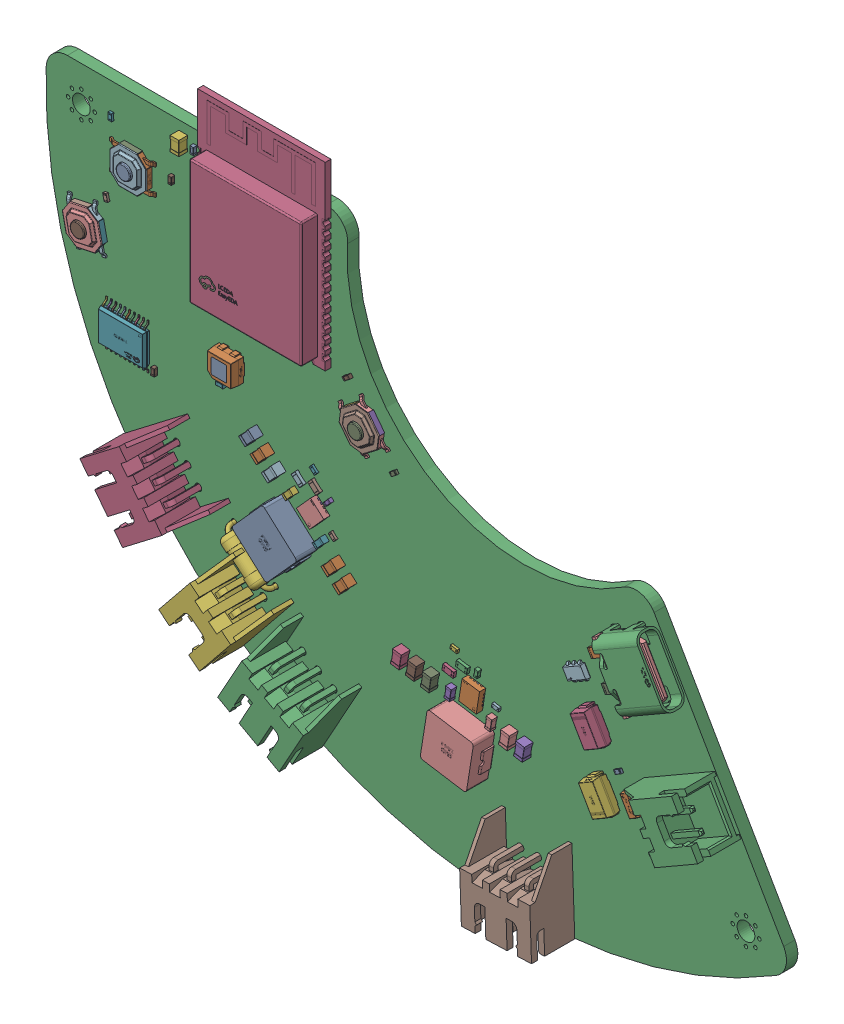
SolidWorks assembly head_control_board(2), configuration Default. Lengths in mm.
Overall size (104.47 78.47 9.5).
115 component instances, 20 part files, 0 mates.
Components (placement in the parent):
- C_0402_1005Metric-1: C_0402_1005Metric [Default] at (-31.1333 33.9184 1.65) x (0 -1 0) z (0 0 1) size (1 0.5 0.5)
  - C_0402_1005Metric-0-1: C_0402_1005Metric-0 [Default] at origin size (1 0.5 0.5)
- R_0805_2012Metric-1: R_0805_2012Metric [Default] at (25.7526 1.0179 1.65) x (0.866025 0.5 0) z (0 0 1) size (2 1.2 0.45)
  - R_0805_2012Metric-1-1: R_0805_2012Metric-1 [Default] at origin size (2 1.2 0.45)
- JST_XH_S2B-XH-A-1_1x02_P2.50mm_Horizontal-1: JST_XH_S2B-XH-A-1_1x02_P2.50mm_Horizontal [Default] at (38.043 -13.5947 1.65) x (-0.5 0.866025 0) z (0 0 1) size (7.4 11.5 9.5)
  - JST_S2B_XH_A_1-1: JST_S2B_XH_A_1 [Default] at origin size (7.4 11.5 9.5)
- C_0805_2012Metric-1: C_0805_2012Metric [Default] at (-1.5819 -13.0649 1.65) x (0.156434 0.987688 0) z (0 0 1) size (2 1.25 1.25)
  - C_0805_2012Metric-2-1: C_0805_2012Metric-2 [Default] at origin size (2 1.25 1.25)
- KEY-SMD_4P-L5.2-W5.2-H1.5-LS6.4-P3.70-1: KEY-SMD_4P-L5.2-W5.2-H1.5-LS6.4-P3.70 [Default] at (-7.2414 12.0071 1.65) x (0.608761 -0.793353 0) z (0 0 1) size (6.4 5.2 1.55)
  - KEY-SMD_4P-L5.2-W5.2-H1.5-LS6.4-P3.70-3-1: KEY-SMD_4P-L5.2-W5.2-H1.5-LS6.4-P3.70-3 [Default] at origin size (6.4 5.2 1.55)
- C_0805_2012Metric-2: C_0805_2012Metric [Default] at (0.5181 -13.4149 1.65) x (0.156434 0.987688 0) z (0 0 1) size (2 1.25 1.25)
  - C_0805_2012Metric-2-1: C_0805_2012Metric-2 [Default] at origin size (2 1.25 1.25)
- SOT-457_L2.9-W1.5-H1.1-P0.95-LS2.8-BL-1: SOT-457_L2.9-W1.5-H1.1-P0.95-LS2.8-BL [Default] at (22.863 -2.9021 1.65) x (-0.866025 -0.5 0) z (0 0 1) size (3.1 3 1.2)
  - SOT-457_L2.9-W1.5-H1.1-P0.95-LS2.8-BL-4-1: SOT-457_L2.9-W1.5-H1.1-P0.95-LS2.8-BL-4 [Default] at origin size (3.1 3 1.2)
- C_0805_2012Metric-3: C_0805_2012Metric [Default] at (-9.4429 -8.0985 1.65) x (0.669131 0.743145 0) z (0 0 1) size (2 1.25 1.25)
  - C_0805_2012Metric-2-1: C_0805_2012Metric-2 [Default] at origin size (2 1.25 1.25)
- C_0402_1005Metric-2: C_0402_1005Metric [Default] at (8.9418 -9.9525 1.65) x (0.156434 0.987688 0) z (0 0 1) size (1 0.5 0.5)
  - C_0402_1005Metric-0-1: C_0402_1005Metric-0 [Default] at origin size (1 0.5 0.5)
- R_0603_1608Metric-1: R_0603_1608Metric [Default] at (4.9519 -11.6475 1.65) x (-0.987688 0.156434 0) z (0 0 1) size (1.6 0.8 0.45)
  - R_0603_1608Metric-5-1: R_0603_1608Metric-5 [Default] at origin size (1.6 0.8 0.45)
- C_0603_1608Metric-1: C_0603_1608Metric [Default] at (5.2667 -14.0766 1.65) x (0.156434 0.987688 0) z (0 0 1) size (1.6 0.8 0.8)
  - C_0603_1608Metric-6-1: C_0603_1608Metric-6 [Default] at origin size (1.6 0.8 0.8)
- SMA_L4.3-W2.6-LS5.2-RD-1: SMA_L4.3-W2.6-LS5.2-RD [Default] at (26.9015 -15.6971 1.65) x (-0.5 0.866025 0) z (0 0 1) size (4.7 2.6 2.1)
  - SMA_L4.3-W2.6-LS5.2-RD-7-1: SMA_L4.3-W2.6-LS5.2-RD-7 [Default] at origin size (4.7 2.6 2.1)
- JST_XH_S3B-XH-A-1_1x03_P2.50mm_Horizontal-1: JST_XH_S3B-XH-A-1_1x03_P2.50mm_Horizontal [Default] at (14.7037 -28.5079 1.65) x (0.999391 0.034899 0) z (0 0 1) size (9.9 11.5 9.5)
  - JST_S3B_XH_A_1-1: JST_S3B_XH_A_1 [Default] at origin size (9.9 11.5 9.5)
- R_0805_2012Metric-2: R_0805_2012Metric [Default] at (27.7276 -2.4029 1.65) x (0.866025 0.5 0) z (0 0 1) size (2 1.2 0.45)
  - R_0805_2012Metric-1-1: R_0805_2012Metric-1 [Default] at origin size (2 1.2 0.45)
- C_0603_1608Metric-2: C_0603_1608Metric [Default] at (10.9917 -14.894 1.65) x (0.156434 0.987688 0) z (0 0 1) size (1.6 0.8 0.8)
  - C_0603_1608Metric-6-1: C_0603_1608Metric-6 [Default] at origin size (1.6 0.8 0.8)
- C_0402_1005Metric-3: C_0402_1005Metric [Default] at (-36.6583 4.1034 1.65) x (0 -1 0) z (0 0 1) size (1 0.5 0.5)
  - C_0402_1005Metric-0-1: C_0402_1005Metric-0 [Default] at origin size (1 0.5 0.5)
- R_0603_1608Metric-2: R_0603_1608Metric [Default] at (-16.2964 1.1254 1.65) x (-0.743145 0.669131 0) z (0 0 1) size (1.6 0.8 0.45)
  - R_0603_1608Metric-5-1: R_0603_1608Metric-5 [Default] at origin size (1.6 0.8 0.45)
- R_0402_1005Metric-1: R_0402_1005Metric [Default] at (28.7584 -12.0966 1.65) x (0.866025 0.5 0) z (0 0 1) size (1 0.5 0.35)
  - R_0402_1005Metric-8-1: R_0402_1005Metric-8 [Default] at origin size (1 0.5 0.35)
- C_0805_2012Metric-4: C_0805_2012Metric [Default] at (-21.0333 2.0234 1.65) x (0.669131 0.743145 0) z (0 0 1) size (2 1.25 1.25)
  - C_0805_2012Metric-2-1: C_0805_2012Metric-2 [Default] at origin size (2 1.25 1.25)
- JST_XH_S3B-XH-A-1_1x03_P2.50mm_Horizontal-2: JST_XH_S3B-XH-A-1_1x03_P2.50mm_Horizontal [Default] at (-16.0229 -19.9395 1.65) x (0.87462 -0.48481 0) z (0 0 1) size (9.9 11.5 9.5)
  - JST_S3B_XH_A_1-1: JST_S3B_XH_A_1 [Default] at origin size (9.9 11.5 9.5)
- JST_XH_S3B-XH-A-1_1x03_P2.50mm_Horizontal-3: JST_XH_S3B-XH-A-1_1x03_P2.50mm_Horizontal [Default] at (-33.7771 -3.3028 1.65) x (0.608761 -0.793353 0) z (0 0 1) size (9.9 11.5 9.5)
  - JST_S3B_XH_A_1-1: JST_S3B_XH_A_1 [Default] at origin size (9.9 11.5 9.5)
- C_0805_2012Metric-5: C_0805_2012Metric [Default] at (15.782 -15.6527 1.65) x (0.156434 0.987688 0) z (0 0 1) size (2 1.25 1.25)
  - C_0805_2012Metric-2-1: C_0805_2012Metric-2 [Default] at origin size (2 1.25 1.25)
- C_0603_1608Metric-3: C_0603_1608Metric [Default] at (-17.3333 -1.0766 1.65) x (0.669131 0.743145 0) z (0 0 1) size (1.6 0.8 0.8)
  - C_0603_1608Metric-6-1: C_0603_1608Metric-6 [Default] at origin size (1.6 0.8 0.8)
- R_0402_1005Metric-2: R_0402_1005Metric [Default] at (-42.8333 32.1134 1.65) x (0 -1 0) z (0 0 1) size (1 0.5 0.35)
  - R_0402_1005Metric-8-1: R_0402_1005Metric-8 [Default] at origin size (1 0.5 0.35)
- R_0603_1608Metric-3: R_0603_1608Metric [Default] at (-13.9833 1.3234 1.65) x (-0.743145 0.669131 0) z (0 0 1) size (1.6 0.8 0.45)
  - R_0603_1608Metric-5-1: R_0603_1608Metric-5 [Default] at origin size (1.6 0.8 0.45)
- KEY-SMD_4P-L5.2-W5.2-H1.5-LS6.4-P3.70-2: KEY-SMD_4P-L5.2-W5.2-H1.5-LS6.4-P3.70 [Default] at (-39.8333 27.3534 1.65) size (6.4 5.2 1.55)
  - KEY-SMD_4P-L5.2-W5.2-H1.5-LS6.4-P3.70-3-1: KEY-SMD_4P-L5.2-W5.2-H1.5-LS6.4-P3.70-3 [Default] at origin size (6.4 5.2 1.55)
- USB-C-SMD_TYPE-C-6PIN-2MD-073-1: USB-C-SMD_TYPE-C-6PIN-2MD-073 [Default] at (33.0237 2.963 3.33) x (-0.5 0.866025 0) z (0 0 1) size (8.95 7.58 4.16)
  - USB-C-SMD_TYPE-C-6PIN-2MD-073-9-1: USB-C-SMD_TYPE-C-6PIN-2MD-073-9 [Default] at origin size (8.95 7.58 4.16)
- JST_XH_S2B-XH-A-1_1x02_P2.50mm_Horizontal-2: JST_XH_S2B-XH-A-1_1x02_P2.50mm_Horizontal [Default] at (-23.4914 -14.4929 1.65) x (0.777146 -0.62932 0) z (0 0 1) size (7.4 11.5 9.5)
  - JST_S2B_XH_A_1-1: JST_S2B_XH_A_1 [Default] at origin size (7.4 11.5 9.5)
- C_0402_1005Metric-4: C_0402_1005Metric [Default] at (-27.2414 7.2321 1.65) x (-1 0 0) z (0 0 1) size (1 0.5 0.5)
  - C_0402_1005Metric-0-1: C_0402_1005Metric-0 [Default] at origin size (1 0.5 0.5)
- R_0402_1005Metric-3: R_0402_1005Metric [Default] at (-43.4893 21.9223 1.65) x (-0.207912 0.978148 0) z (0 0 1) size (1 0.5 0.35)
  - R_0402_1005Metric-8-1: R_0402_1005Metric-8 [Default] at origin size (1 0.5 0.35)
- R_0402_1005Metric-4: R_0402_1005Metric [Default] at (-2.8879 8.5129 1.65) x (-0.793353 -0.608761 0) z (0 0 1) size (1 0.5 0.35)
  - R_0402_1005Metric-8-1: R_0402_1005Metric-8 [Default] at origin size (1 0.5 0.35)
- IND-SMD_L7.0-W6.6-H3.0-1: IND-SMD_L7.0-W6.6-H3.0 [Default] at (7.4599 -18.8148 1.65) x (-0.987688 0.156434 0) z (0 0 1) size (7.01 6.6 3.1)
  - IND-SMD_L7.0-W6.6-H3.0-10-1: IND-SMD_L7.0-W6.6-H3.0-10 [Default] at origin size (7.01 6.6 3.1)
- C_0402_1005Metric-5: C_0402_1005Metric [Default] at (-34.2583 28.7234 1.65) x (0 1 0) z (0 0 1) size (1 0.5 0.5)
  - C_0402_1005Metric-0-1: C_0402_1005Metric-0 [Default] at origin size (1 0.5 0.5)
- VQFN-HR-15_L3.0-W2.5-H0.9-P0.50-BL_TPS63070RNMR-1: VQFN-HR-15_L3.0-W2.5-H0.9-P0.50-BL_TPS63070RNMR [Default] at (8.4102 -12.7623 1.65) x (-0.987688 0.156434 0) z (0 0 1) size (2.5 3 0.9)
  - VQFN-HR-15_L3.0-W2.5-H0.9-P0.50-BL_TPS63070RNMR-11-1: VQFN-HR-15_L3.0-W2.5-H0.9-P0.50-BL_TPS63070RNMR-11 [Default] at origin size (2.5 3 0.9)
- SMA_L4.3-W2.6-LS5.2-RD-2: SMA_L4.3-W2.6-LS5.2-RD [Default] at (25.713 -7.8385 1.65) x (0.5 -0.866025 0) z (0 0 1) size (4.7 2.6 2.1)
  - SMA_L4.3-W2.6-LS5.2-RD-7-1: SMA_L4.3-W2.6-LS5.2-RD-7 [Default] at origin size (4.7 2.6 2.1)
- R_Axial_DIN0207_L6.3mm_D2.5mm_P7.62mm_Horizontal-1: R_Axial_DIN0207_L6.3mm_D2.5mm_P7.62mm_Horizontal [Default] at (-25.6833 -9.0016 1.65) x (0.766044 -0.642788 0) z (0 0 1) size (8.22 2.5 5.5)
  - R_Axial_DIN0207_L63mm_D25mm_P762mm_Horizontal-1: R_Axial_DIN0207_L63mm_D25mm_P762mm_Horizontal [Default] at origin size (8.22 2.5 5.5)
- TSSOP-20_L6.5-W4.4-H1.0-LS6.4-P0.65-1: TSSOP-20_L6.5-W4.4-H1.0-LS6.4-P0.65 [Default] at (-40.6464 6.4771 1.65) x (0 -1 0) z (0 0 1) size (6.41 6.5 1.05)
  - TSSOP-20_L6.5-W4.4-H1.0-LS6.4-P0.65-12-1: TSSOP-20_L6.5-W4.4-H1.0-LS6.4-P0.65-12 [Default] at origin size (6.41 6.5 1.05)
- C_0402_1005Metric-6: C_0402_1005Metric [Default] at (-12.0621 0.4301 1.65) x (0.669131 0.743145 0) z (0 0 1) size (1 0.5 0.5)
  - C_0402_1005Metric-0-1: C_0402_1005Metric-0 [Default] at origin size (1 0.5 0.5)
- C_0805_2012Metric-6: C_0805_2012Metric [Default] at (-32.8083 34.0225 1.65) x (0 -1 0) z (0 0 1) size (2 1.25 1.25)
  - C_0805_2012Metric-2-1: C_0805_2012Metric-2 [Default] at origin size (2 1.25 1.25)
- C_0603_1608Metric-4: C_0603_1608Metric [Default] at (-13.0286 -4.87 1.65) x (0.669131 0.743145 0) z (0 0 1) size (1.6 0.8 0.8)
  - C_0603_1608Metric-6-1: C_0603_1608Metric-6 [Default] at origin size (1.6 0.8 0.8)
- VQFN-HR-15_L3.0-W2.5-H0.9-P0.50-BL_TPS63070RNMR-2: VQFN-HR-15_L3.0-W2.5-H0.9-P0.50-BL_TPS63070RNMR [Default] at (-14.0242 -1.6792 1.65) x (-0.743145 0.669131 0) z (0 0 1) size (2.5 3 0.9)
  - VQFN-HR-15_L3.0-W2.5-H0.9-P0.50-BL_TPS63070RNMR-11-1: VQFN-HR-15_L3.0-W2.5-H0.9-P0.50-BL_TPS63070RNMR-11 [Default] at origin size (2.5 3 0.9)
- C_0805_2012Metric-7: C_0805_2012Metric [Default] at (-19.4333 0.5734 1.65) x (0.669131 0.743145 0) z (0 0 1) size (2 1.25 1.25)
  - C_0805_2012Metric-2-1: C_0805_2012Metric-2 [Default] at origin size (2 1.25 1.25)
- C_0805_2012Metric-8: C_0805_2012Metric [Default] at (-22.6333 3.4234 1.65) x (0.669131 0.743145 0) z (0 0 1) size (2 1.25 1.25)
  - C_0805_2012Metric-2-1: C_0805_2012Metric-2 [Default] at origin size (2 1.25 1.25)
- SOT-23-3P_L2.9-W1.3-H1.0-LS2.4-P0.95-1: SOT-23-3P_L2.9-W1.3-H1.0-LS2.4-P0.95 [Default] at (31.0339 -14.7546 1.65) x (0.866025 0.5 0) z (0 0 1) size (2.51 2.9 1.05)
  - SOT-23-3P_L2.9-W1.3-H1.0-LS2.4-P0.95-13-1: SOT-23-3P_L2.9-W1.3-H1.0-LS2.4-P0.95-13 [Default] at origin size (2.51 2.9 1.05)
- KEY-SMD_4P-L5.2-W5.2-H1.5-LS6.4-P3.70-3: KEY-SMD_4P-L5.2-W5.2-H1.5-LS6.4-P3.70 [Default] at (-46.3174 17.0825 1.65) x (0.207912 -0.978148 0) z (0 0 1) size (6.4 5.2 1.55)
  - KEY-SMD_4P-L5.2-W5.2-H1.5-LS6.4-P3.70-3-1: KEY-SMD_4P-L5.2-W5.2-H1.5-LS6.4-P3.70-3 [Default] at origin size (6.4 5.2 1.55)
- IND-SMD_L7.0-W6.6-H3.0-2: IND-SMD_L7.0-W6.6-H3.0 [Default] at (-18.2824 -6.4054 1.65) x (-0.743145 0.669131 0) z (0 0 1) size (7.01 6.6 3.1)
  - IND-SMD_L7.0-W6.6-H3.0-10-1: IND-SMD_L7.0-W6.6-H3.0-10 [Default] at origin size (7.01 6.6 3.1)
- C_0805_2012Metric-9: C_0805_2012Metric [Default] at (-11.0221 -6.6766 1.65) x (0.669131 0.743145 0) z (0 0 1) size (2 1.25 1.25)
  - C_0805_2012Metric-2-1: C_0805_2012Metric-2 [Default] at origin size (2 1.25 1.25)
- R_0603_1608Metric-4: R_0603_1608Metric [Default] at (6.8667 -10.2266 1.65) x (-0.987688 0.156434 0) z (0 0 1) size (1.6 0.8 0.45)
  - R_0603_1608Metric-5-1: R_0603_1608Metric-5 [Default] at origin size (1.6 0.8 0.45)
- WIRELM-SMD_ESP32-S3-WROOM-1-1: WIRELM-SMD_ESP32-S3-WROOM-1 [Default] at (-20.9833 29.4704 1.65) size (18 25.5 3.11)
  - WIRELM-SMD_ESP32-S3-WROOM-1-14-1: WIRELM-SMD_ESP32-S3-WROOM-1-14 [Default] at origin size (18 25.5 3.11)
- R_0402_1005Metric-5: R_0402_1005Metric [Default] at (5.6667 -8.6766 1.65) x (0.987688 -0.156434 0) z (0 0 1) size (1 0.5 0.35)
  - R_0402_1005Metric-8-1: R_0402_1005Metric-8 [Default] at origin size (1 0.5 0.35)
- R_0402_1005Metric-6: R_0402_1005Metric [Default] at (-14.1833 3.2734 1.65) x (0.743145 -0.669131 0) z (0 0 1) size (1 0.5 0.35)
  - R_0402_1005Metric-8-1: R_0402_1005Metric-8 [Default] at origin size (1 0.5 0.35)
- R_0402_1005Metric-7: R_0402_1005Metric [Default] at (-11.4896 -3.4971 1.65) x (-0.743145 0.669131 0) z (0 0 1) size (1 0.5 0.35)
  - R_0402_1005Metric-8-1: R_0402_1005Metric-8 [Default] at origin size (1 0.5 0.35)
- C_0805_2012Metric-10: C_0805_2012Metric [Default] at (2.6181 -13.7649 1.65) x (0.156434 0.987688 0) z (0 0 1) size (2 1.25 1.25)
  - C_0805_2012Metric-2-1: C_0805_2012Metric-2 [Default] at origin size (2 1.25 1.25)
- C_0805_2012Metric-11: C_0805_2012Metric [Default] at (13.6584 -15.3164 1.65) x (0.156434 0.987688 0) z (0 0 1) size (2 1.25 1.25)
  - C_0805_2012Metric-2-1: C_0805_2012Metric-2 [Default] at origin size (2 1.25 1.25)
- C_0402_1005Metric-7: C_0402_1005Metric [Default] at (-9.3775 17.0156 1.65) x (-0.793353 -0.608761 0) z (0 0 1) size (1 0.5 0.5)
  - C_0402_1005Metric-0-1: C_0402_1005Metric-0 [Default] at origin size (1 0.5 0.5)
- R_0402_1005Metric-8: R_0402_1005Metric [Default] at (11.5237 -12.8774 1.65) x (-0.987688 0.156434 0) z (0 0 1) size (1 0.5 0.35)
  - R_0402_1005Metric-8-1: R_0402_1005Metric-8 [Default] at origin size (1 0.5 0.35)
- LED3535-4P_L3.5-W3.5-H1.9-LS3.7-1: LED3535-4P_L3.5-W3.5-H1.9-LS3.7 [Default] at (-25.8764 10.4671 1.65) x (0 1 0) z (0 0 1) size (3.5 3.51 1.94)
  - LED3535-4P_L3.5-W3.5-H1.9-LS3.7-15-1: LED3535-4P_L3.5-W3.5-H1.9-LS3.7-15 [Default] at origin size (3.5 3.51 1.94)
- head_control_board_PCB-1: head_control_board_PCB [Default] at origin size (104.47 72.5 1.6)
